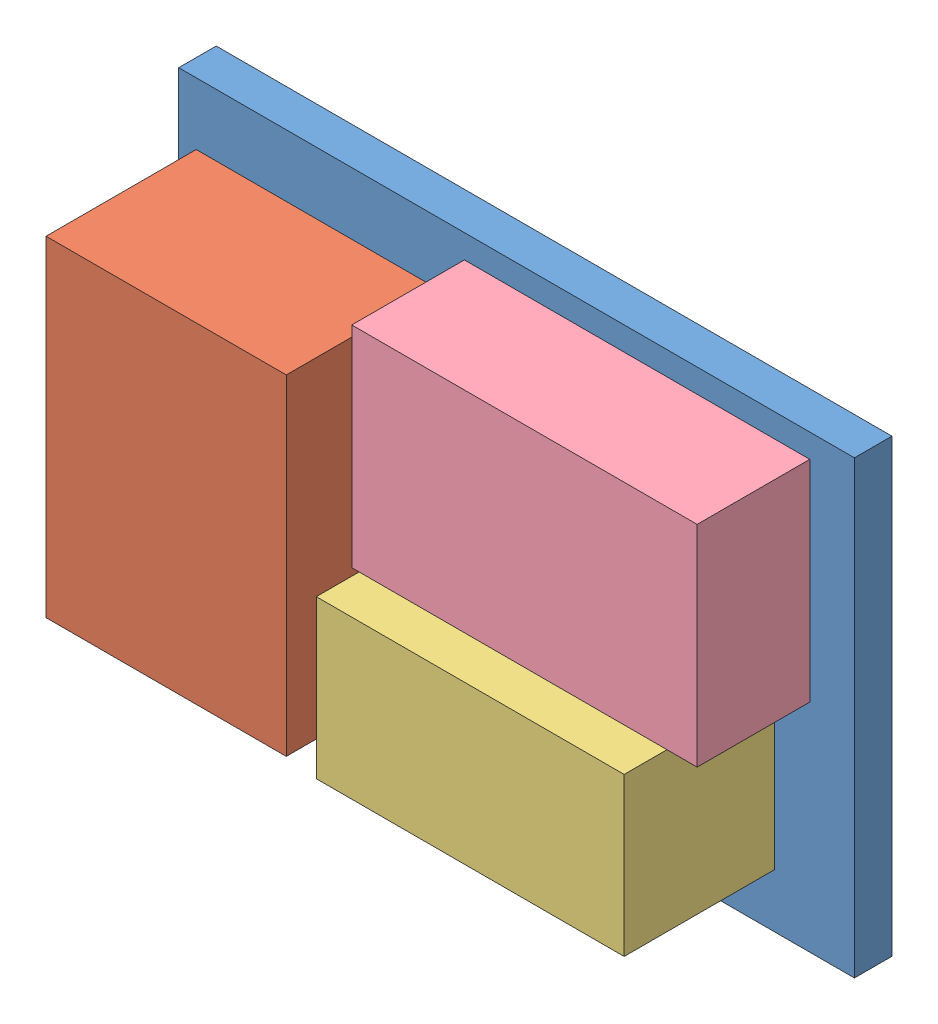
SolidWorks assembly Assem1, configuration Default. Lengths in mm.
Overall size (90 60 25).
4 component instances, 4 part files, 5 mates.
Components (placement in the parent):
- PCB-1: PCB [Default] at (14.099 177.9129 275.6556) size (90 60 5)
- VoltageRegulatorMotor-1: VoltageRegulatorMotor [Default] at (48.4321 185.6401 280.6556) x (0 1 0) z (0 0 1) size (44 32 20)
- VoltageRegulatorOdroid-1: VoltageRegulatorOdroid [Default] at (52.4291 185.0608 280.6556) size (41 21 20)
- MotorDriver-2: MotorDriver [Default] at (98.1508 234.7631 280.6556) x (-1 0 0) z (0 0 1) size (46 28 15)
Mates (geometry in assembly coordinates):
- Coincident1: coincident anti-aligned: plane of PCB-1 through (14.099 177.9129 280.6556) normal (0 0 1); plane of VoltageRegulatorMotor-1 through (48.4321 185.6401 280.6556) normal (0 0 -1)
- Coincident2: coincident anti-aligned: plane of PCB-1 through (14.099 177.9129 280.6556) normal (0 0 1); plane of MotorDriver-2 through (98.1508 234.7631 280.6556) normal (0 0 -1)
- Coincident3: coincident anti-aligned: plane of PCB-1 through (14.099 177.9129 280.6556) normal (0 0 1); plane of VoltageRegulatorOdroid-1 through (52.4291 185.0608 280.6556) normal (0 0 -1)
- Parallel2: parallel anti-aligned: plane of PCB-1 through (14.099 237.9129 280.6556) normal (0 1 0); plane of VoltageRegulatorMotor-1 through (48.4321 185.6401 300.6556) normal (0 -1 0)
- Parallel3: parallel anti-aligned: plane of PCB-1 through (104.099 177.9129 280.6556) normal (1 0 0); plane of MotorDriver-2 through (52.1508 234.7631 295.6556) normal (-1 0 0)
